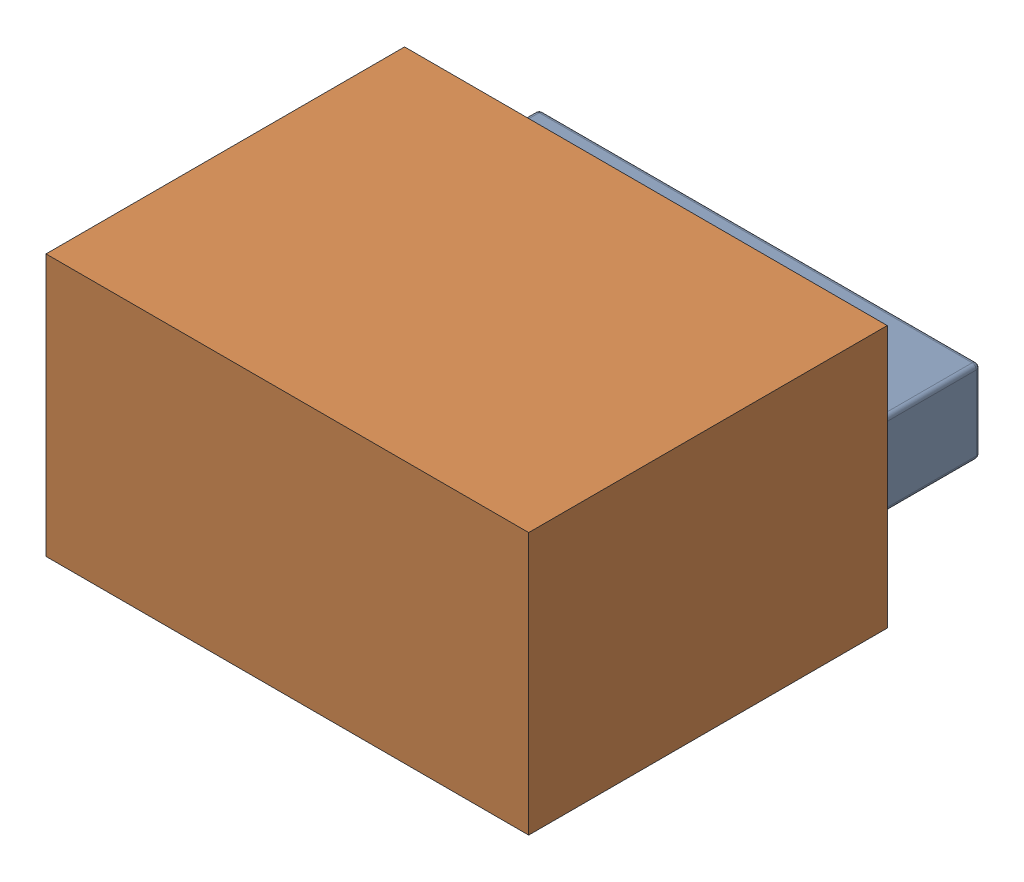
SolidWorks assembly D2, configuration Default. Lengths in mm.
Overall size (1.75 0.95 1.7).
3 component instances, 2 part files, 0 mates.
Components (placement in the parent):
- User_Library-0603_SMD_Capacitor-1: User_Library-0603_SMD_Capacitor [Default] at (40.9068 93.71 0) x (-1 0 0) z (0 0 1) size (1.6 0.31 0.8)
- 642239760-1: 642239760 [Default] at (40.894 93.583 0) size (1.75 0.95 1.3)
  - Extruded_4-1: Extruded_4 [Default] at origin size (1.75 0.95 1.3)
